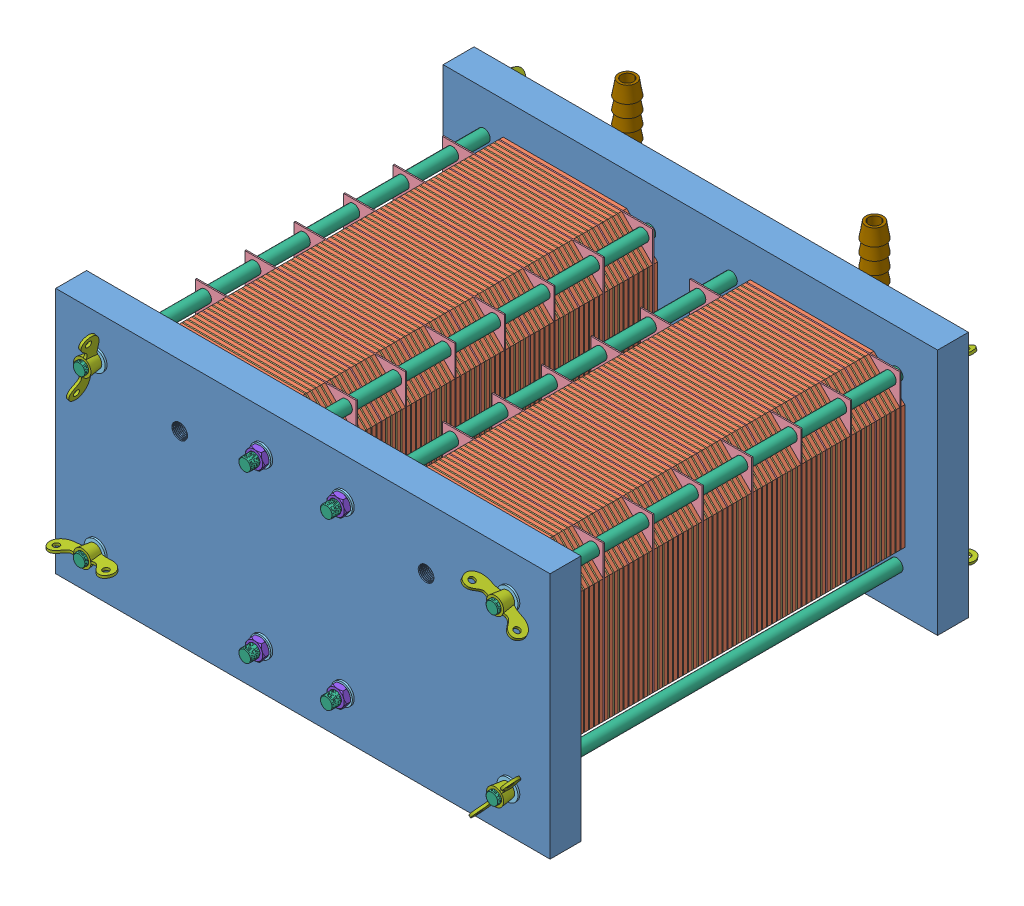
SolidWorks assembly Assem_Mine, configuration Default. Lengths in mm.
Overall size (400 216 390.22).
346 component instances, 9 part files, 95 mates.
Components (placement in the parent):
- Glass-1: Glass [Default] at (153.2199 -57.0551 297.1136) size (400 200 26.12)
- All Battery Block-1: All Battery Block [Default] at (-10.6585 129.0849 -81.5684) size (150 150 287)
  - Block Battery-1: Block Battery [Default] at (-175.922 -206.6429 -286.6039) size (150 150 40)
    - Gasket-12: Gasket [Default] at (244.3004 275.7985 390.286) size (150 150 3)
    - Plate-1-7: Plate-1 [Default] at (239.8004 279.4658 389.286) size (150 150 1)
    - Gasket-13: Gasket [Default] at (244.3004 275.7985 386.286) size (150 150 3)
    - Plate-1-8: Plate-1 [Default] at (239.8004 279.4658 385.286) size (150 150 1)
    - Gasket-14: Gasket [Default] at (244.3004 275.7985 382.286) size (150 150 3)
    - Plate-2-4: Plate-2 [Default] at (239.8004 279.4658 381.286) size (150 150 1)
    - Plate-1-10: Plate-1 [Default] at (239.8004 279.4658 393.286) size (150 150 1)
    - Gasket-16: Gasket [Default] at (244.3004 275.7985 394.286) size (150 150 3)
    - Plate-1-11: Plate-1 [Default] at (239.8004 279.4658 397.286) size (150 150 1)
    - Gasket-17: Gasket [Default] at (244.3004 275.7985 398.286) size (150 150 3)
    - Plate-2-5: Plate-2 [Default] at (239.8004 279.4658 402.286) x (-1 0 0) z (0 0 -1) size (150 150 1)
    - Gasket-18: Gasket [Default] at (244.3004 275.7985 402.286) size (150 150 3)
    - Plate-1-12: Plate-1 [Default] at (239.8004 279.4658 405.286) size (150 150 1)
    - Gasket-19: Gasket [Default] at (244.3004 275.7985 406.286) size (150 150 3)
    - Plate-1-13: Plate-1 [Default] at (239.8004 279.4658 409.286) size (150 150 1)
    - Gasket-20: Gasket [Default] at (244.3004 275.7985 410.286) size (150 150 3)
    - Plate-1-14: Plate-1 [Default] at (239.8004 279.4658 413.286) size (150 150 1)
    - Gasket-21: Gasket [Default] at (244.3004 275.7985 414.286) size (150 150 3)
    - Plate-1-15: Plate-1 [Default] at (239.8004 279.4658 417.286) size (150 150 1)
    - Gasket-22: Gasket [Default] at (244.3004 275.7985 418.286) size (150 150 3)
  - Block Battery-2: Block Battery [Default] at (-175.922 -206.6429 -246.6039) size (150 150 40)
    - Gasket-12: Gasket [Default] at (244.3004 275.7985 390.286) size (150 150 3)
    - Plate-1-7: Plate-1 [Default] at (239.8004 279.4658 389.286) size (150 150 1)
    - Gasket-13: Gasket [Default] at (244.3004 275.7985 386.286) size (150 150 3)
    - Plate-1-8: Plate-1 [Default] at (239.8004 279.4658 385.286) size (150 150 1)
    - Gasket-14: Gasket [Default] at (244.3004 275.7985 382.286) size (150 150 3)
    - Plate-2-4: Plate-2 [Default] at (239.8004 279.4658 381.286) size (150 150 1)
    - Plate-1-10: Plate-1 [Default] at (239.8004 279.4658 393.286) size (150 150 1)
    - Gasket-16: Gasket [Default] at (244.3004 275.7985 394.286) size (150 150 3)
    - Plate-1-11: Plate-1 [Default] at (239.8004 279.4658 397.286) size (150 150 1)
    - Gasket-17: Gasket [Default] at (244.3004 275.7985 398.286) size (150 150 3)
    - Plate-2-5: Plate-2 [Default] at (239.8004 279.4658 402.286) x (-1 0 0) z (0 0 -1) size (150 150 1)
    - Gasket-18: Gasket [Default] at (244.3004 275.7985 402.286) size (150 150 3)
    - Plate-1-12: Plate-1 [Default] at (239.8004 279.4658 405.286) size (150 150 1)
    - Gasket-19: Gasket [Default] at (244.3004 275.7985 406.286) size (150 150 3)
    - Plate-1-13: Plate-1 [Default] at (239.8004 279.4658 409.286) size (150 150 1)
    - Gasket-20: Gasket [Default] at (244.3004 275.7985 410.286) size (150 150 3)
    - Plate-1-14: Plate-1 [Default] at (239.8004 279.4658 413.286) size (150 150 1)
    - Gasket-21: Gasket [Default] at (244.3004 275.7985 414.286) size (150 150 3)
    - Plate-1-15: Plate-1 [Default] at (239.8004 279.4658 417.286) size (150 150 1)
    - Gasket-22: Gasket [Default] at (244.3004 275.7985 418.286) size (150 150 3)
  - Block Battery-3: Block Battery [Default] at (-175.922 -206.6429 -206.6039) size (150 150 40)
    - Gasket-12: Gasket [Default] at (244.3004 275.7985 390.286) size (150 150 3)
    - Plate-1-7: Plate-1 [Default] at (239.8004 279.4658 389.286) size (150 150 1)
    - Gasket-13: Gasket [Default] at (244.3004 275.7985 386.286) size (150 150 3)
    - Plate-1-8: Plate-1 [Default] at (239.8004 279.4658 385.286) size (150 150 1)
    - Gasket-14: Gasket [Default] at (244.3004 275.7985 382.286) size (150 150 3)
    - Plate-2-4: Plate-2 [Default] at (239.8004 279.4658 381.286) size (150 150 1)
    - Plate-1-10: Plate-1 [Default] at (239.8004 279.4658 393.286) size (150 150 1)
    - Gasket-16: Gasket [Default] at (244.3004 275.7985 394.286) size (150 150 3)
    - Plate-1-11: Plate-1 [Default] at (239.8004 279.4658 397.286) size (150 150 1)
    - Gasket-17: Gasket [Default] at (244.3004 275.7985 398.286) size (150 150 3)
    - Plate-2-5: Plate-2 [Default] at (239.8004 279.4658 402.286) x (-1 0 0) z (0 0 -1) size (150 150 1)
    - Gasket-18: Gasket [Default] at (244.3004 275.7985 402.286) size (150 150 3)
    - Plate-1-12: Plate-1 [Default] at (239.8004 279.4658 405.286) size (150 150 1)
    - Gasket-19: Gasket [Default] at (244.3004 275.7985 406.286) size (150 150 3)
    - Plate-1-13: Plate-1 [Default] at (239.8004 279.4658 409.286) size (150 150 1)
    - Gasket-20: Gasket [Default] at (244.3004 275.7985 410.286) size (150 150 3)
    - Plate-1-14: Plate-1 [Default] at (239.8004 279.4658 413.286) size (150 150 1)
    - Gasket-21: Gasket [Default] at (244.3004 275.7985 414.286) size (150 150 3)
    - Plate-1-15: Plate-1 [Default] at (239.8004 279.4658 417.286) size (150 150 1)
    - Gasket-22: Gasket [Default] at (244.3004 275.7985 418.286) size (150 150 3)
  - Block Battery-4: Block Battery [Default] at (-175.922 -206.6429 -166.6039) size (150 150 40)
    - Gasket-12: Gasket [Default] at (244.3004 275.7985 390.286) size (150 150 3)
    - Plate-1-7: Plate-1 [Default] at (239.8004 279.4658 389.286) size (150 150 1)
    - Gasket-13: Gasket [Default] at (244.3004 275.7985 386.286) size (150 150 3)
    - Plate-1-8: Plate-1 [Default] at (239.8004 279.4658 385.286) size (150 150 1)
    - Gasket-14: Gasket [Default] at (244.3004 275.7985 382.286) size (150 150 3)
    - Plate-2-4: Plate-2 [Default] at (239.8004 279.4658 381.286) size (150 150 1)
    - Plate-1-10: Plate-1 [Default] at (239.8004 279.4658 393.286) size (150 150 1)
    - Gasket-16: Gasket [Default] at (244.3004 275.7985 394.286) size (150 150 3)
    - Plate-1-11: Plate-1 [Default] at (239.8004 279.4658 397.286) size (150 150 1)
    - Gasket-17: Gasket [Default] at (244.3004 275.7985 398.286) size (150 150 3)
    - Plate-2-5: Plate-2 [Default] at (239.8004 279.4658 402.286) x (-1 0 0) z (0 0 -1) size (150 150 1)
    - Gasket-18: Gasket [Default] at (244.3004 275.7985 402.286) size (150 150 3)
    - Plate-1-12: Plate-1 [Default] at (239.8004 279.4658 405.286) size (150 150 1)
    - Gasket-19: Gasket [Default] at (244.3004 275.7985 406.286) size (150 150 3)
    - Plate-1-13: Plate-1 [Default] at (239.8004 279.4658 409.286) size (150 150 1)
    - Gasket-20: Gasket [Default] at (244.3004 275.7985 410.286) size (150 150 3)
    - Plate-1-14: Plate-1 [Default] at (239.8004 279.4658 413.286) size (150 150 1)
    - Gasket-21: Gasket [Default] at (244.3004 275.7985 414.286) size (150 150 3)
    - Plate-1-15: Plate-1 [Default] at (239.8004 279.4658 417.286) size (150 150 1)
    - Gasket-22: Gasket [Default] at (244.3004 275.7985 418.286) size (150 150 3)
  - Block Battery-5: Block Battery [Default] at (-175.922 -206.6429 -126.6039) size (150 150 40)
    - Gasket-12: Gasket [Default] at (244.3004 275.7985 390.286) size (150 150 3)
    - Plate-1-7: Plate-1 [Default] at (239.8004 279.4658 389.286) size (150 150 1)
    - Gasket-13: Gasket [Default] at (244.3004 275.7985 386.286) size (150 150 3)
    - Plate-1-8: Plate-1 [Default] at (239.8004 279.4658 385.286) size (150 150 1)
    - Gasket-14: Gasket [Default] at (244.3004 275.7985 382.286) size (150 150 3)
    - Plate-2-4: Plate-2 [Default] at (239.8004 279.4658 381.286) size (150 150 1)
    - Plate-1-10: Plate-1 [Default] at (239.8004 279.4658 393.286) size (150 150 1)
    - Gasket-16: Gasket [Default] at (244.3004 275.7985 394.286) size (150 150 3)
    - Plate-1-11: Plate-1 [Default] at (239.8004 279.4658 397.286) size (150 150 1)
    - Gasket-17: Gasket [Default] at (244.3004 275.7985 398.286) size (150 150 3)
    - Plate-2-5: Plate-2 [Default] at (239.8004 279.4658 402.286) x (-1 0 0) z (0 0 -1) size (150 150 1)
    - Gasket-18: Gasket [Default] at (244.3004 275.7985 402.286) size (150 150 3)
    - Plate-1-12: Plate-1 [Default] at (239.8004 279.4658 405.286) size (150 150 1)
    - Gasket-19: Gasket [Default] at (244.3004 275.7985 406.286) size (150 150 3)
    - Plate-1-13: Plate-1 [Default] at (239.8004 279.4658 409.286) size (150 150 1)
    - Gasket-20: Gasket [Default] at (244.3004 275.7985 410.286) size (150 150 3)
    - Plate-1-14: Plate-1 [Default] at (239.8004 279.4658 413.286) size (150 150 1)
    - Gasket-21: Gasket [Default] at (244.3004 275.7985 414.286) size (150 150 3)
    - Plate-1-15: Plate-1 [Default] at (239.8004 279.4658 417.286) size (150 150 1)
    - Gasket-22: Gasket [Default] at (244.3004 275.7985 418.286) size (150 150 3)
  - Block Battery-6: Block Battery [Default] at (-175.922 -206.6429 -86.6039) size (150 150 40)
    - Gasket-12: Gasket [Default] at (244.3004 275.7985 390.286) size (150 150 3)
    - Plate-1-7: Plate-1 [Default] at (239.8004 279.4658 389.286) size (150 150 1)
    - Gasket-13: Gasket [Default] at (244.3004 275.7985 386.286) size (150 150 3)
    - Plate-1-8: Plate-1 [Default] at (239.8004 279.4658 385.286) size (150 150 1)
    - Gasket-14: Gasket [Default] at (244.3004 275.7985 382.286) size (150 150 3)
    - Plate-2-4: Plate-2 [Default] at (239.8004 279.4658 381.286) size (150 150 1)
    - Plate-1-10: Plate-1 [Default] at (239.8004 279.4658 393.286) size (150 150 1)
    - Gasket-16: Gasket [Default] at (244.3004 275.7985 394.286) size (150 150 3)
    - Plate-1-11: Plate-1 [Default] at (239.8004 279.4658 397.286) size (150 150 1)
    - Gasket-17: Gasket [Default] at (244.3004 275.7985 398.286) size (150 150 3)
    - Plate-2-5: Plate-2 [Default] at (239.8004 279.4658 402.286) x (-1 0 0) z (0 0 -1) size (150 150 1)
    - Gasket-18: Gasket [Default] at (244.3004 275.7985 402.286) size (150 150 3)
    - Plate-1-12: Plate-1 [Default] at (239.8004 279.4658 405.286) size (150 150 1)
    - Gasket-19: Gasket [Default] at (244.3004 275.7985 406.286) size (150 150 3)
    - Plate-1-13: Plate-1 [Default] at (239.8004 279.4658 409.286) size (150 150 1)
    - Gasket-20: Gasket [Default] at (244.3004 275.7985 410.286) size (150 150 3)
    - Plate-1-14: Plate-1 [Default] at (239.8004 279.4658 413.286) size (150 150 1)
    - Gasket-21: Gasket [Default] at (244.3004 275.7985 414.286) size (150 150 3)
    - Plate-1-15: Plate-1 [Default] at (239.8004 279.4658 417.286) size (150 150 1)
    - Gasket-22: Gasket [Default] at (244.3004 275.7985 418.286) size (150 150 3)
  - Block Battery-7: Block Battery [Default] at (-175.922 -206.6429 -46.6039) size (150 150 40)
    - Gasket-12: Gasket [Default] at (244.3004 275.7985 390.286) size (150 150 3)
    - Plate-1-7: Plate-1 [Default] at (239.8004 279.4658 389.286) size (150 150 1)
    - Gasket-13: Gasket [Default] at (244.3004 275.7985 386.286) size (150 150 3)
    - Plate-1-8: Plate-1 [Default] at (239.8004 279.4658 385.286) size (150 150 1)
    - Gasket-14: Gasket [Default] at (244.3004 275.7985 382.286) size (150 150 3)
    - Plate-2-4: Plate-2 [Default] at (239.8004 279.4658 381.286) size (150 150 1)
    - Plate-1-10: Plate-1 [Default] at (239.8004 279.4658 393.286) size (150 150 1)
    - Gasket-16: Gasket [Default] at (244.3004 275.7985 394.286) size (150 150 3)
    - Plate-1-11: Plate-1 [Default] at (239.8004 279.4658 397.286) size (150 150 1)
    - Gasket-17: Gasket [Default] at (244.3004 275.7985 398.286) size (150 150 3)
    - Plate-2-5: Plate-2 [Default] at (239.8004 279.4658 402.286) x (-1 0 0) z (0 0 -1) size (150 150 1)
    - Gasket-18: Gasket [Default] at (244.3004 275.7985 402.286) size (150 150 3)
    - Plate-1-12: Plate-1 [Default] at (239.8004 279.4658 405.286) size (150 150 1)
    - Gasket-19: Gasket [Default] at (244.3004 275.7985 406.286) size (150 150 3)
    - Plate-1-13: Plate-1 [Default] at (239.8004 279.4658 409.286) size (150 150 1)
    - Gasket-20: Gasket [Default] at (244.3004 275.7985 410.286) size (150 150 3)
    - Plate-1-14: Plate-1 [Default] at (239.8004 279.4658 413.286) size (150 150 1)
    - Gasket-21: Gasket [Default] at (244.3004 275.7985 414.286) size (150 150 3)
    - Plate-1-15: Plate-1 [Default] at (239.8004 279.4658 417.286) size (150 150 1)
    - Gasket-22: Gasket [Default] at (244.3004 275.7985 418.286) size (150 150 3)
  - Plate-2-1: Plate-2 [Default] at (63.8784 72.8229 374.682) size (150 150 1)
  - Gasket-1: Gasket [Default] at (68.3784 69.1556 375.682) size (150 150 3)
  - Gasket-2: Gasket [Default] at (68.3784 69.1556 91.682) size (150 150 3)
- All Battery Block-2: All Battery Block [Default] at (189.3415 129.0849 -81.5684) size (150 150 287)
  - Block Battery-1: Block Battery [Default] at (-175.922 -206.6429 -286.6039) size (150 150 40)
    - Gasket-12: Gasket [Default] at (244.3004 275.7985 390.286) size (150 150 3)
    - Plate-1-7: Plate-1 [Default] at (239.8004 279.4658 389.286) size (150 150 1)
    - Gasket-13: Gasket [Default] at (244.3004 275.7985 386.286) size (150 150 3)
    - Plate-1-8: Plate-1 [Default] at (239.8004 279.4658 385.286) size (150 150 1)
    - Gasket-14: Gasket [Default] at (244.3004 275.7985 382.286) size (150 150 3)
    - Plate-2-4: Plate-2 [Default] at (239.8004 279.4658 381.286) size (150 150 1)
    - Plate-1-10: Plate-1 [Default] at (239.8004 279.4658 393.286) size (150 150 1)
    - Gasket-16: Gasket [Default] at (244.3004 275.7985 394.286) size (150 150 3)
    - Plate-1-11: Plate-1 [Default] at (239.8004 279.4658 397.286) size (150 150 1)
    - Gasket-17: Gasket [Default] at (244.3004 275.7985 398.286) size (150 150 3)
    - Plate-2-5: Plate-2 [Default] at (239.8004 279.4658 402.286) x (-1 0 0) z (0 0 -1) size (150 150 1)
    - Gasket-18: Gasket [Default] at (244.3004 275.7985 402.286) size (150 150 3)
    - Plate-1-12: Plate-1 [Default] at (239.8004 279.4658 405.286) size (150 150 1)
    - Gasket-19: Gasket [Default] at (244.3004 275.7985 406.286) size (150 150 3)
    - Plate-1-13: Plate-1 [Default] at (239.8004 279.4658 409.286) size (150 150 1)
    - Gasket-20: Gasket [Default] at (244.3004 275.7985 410.286) size (150 150 3)
    - Plate-1-14: Plate-1 [Default] at (239.8004 279.4658 413.286) size (150 150 1)
    - Gasket-21: Gasket [Default] at (244.3004 275.7985 414.286) size (150 150 3)
    - Plate-1-15: Plate-1 [Default] at (239.8004 279.4658 417.286) size (150 150 1)
    - Gasket-22: Gasket [Default] at (244.3004 275.7985 418.286) size (150 150 3)
  - Block Battery-2: Block Battery [Default] at (-175.922 -206.6429 -246.6039) size (150 150 40)
    - Gasket-12: Gasket [Default] at (244.3004 275.7985 390.286) size (150 150 3)
    - Plate-1-7: Plate-1 [Default] at (239.8004 279.4658 389.286) size (150 150 1)
    - Gasket-13: Gasket [Default] at (244.3004 275.7985 386.286) size (150 150 3)
    - Plate-1-8: Plate-1 [Default] at (239.8004 279.4658 385.286) size (150 150 1)
    - Gasket-14: Gasket [Default] at (244.3004 275.7985 382.286) size (150 150 3)
    - Plate-2-4: Plate-2 [Default] at (239.8004 279.4658 381.286) size (150 150 1)
    - Plate-1-10: Plate-1 [Default] at (239.8004 279.4658 393.286) size (150 150 1)
    - Gasket-16: Gasket [Default] at (244.3004 275.7985 394.286) size (150 150 3)
    - Plate-1-11: Plate-1 [Default] at (239.8004 279.4658 397.286) size (150 150 1)
    - Gasket-17: Gasket [Default] at (244.3004 275.7985 398.286) size (150 150 3)
    - Plate-2-5: Plate-2 [Default] at (239.8004 279.4658 402.286) x (-1 0 0) z (0 0 -1) size (150 150 1)
    - Gasket-18: Gasket [Default] at (244.3004 275.7985 402.286) size (150 150 3)
    - Plate-1-12: Plate-1 [Default] at (239.8004 279.4658 405.286) size (150 150 1)
    - Gasket-19: Gasket [Default] at (244.3004 275.7985 406.286) size (150 150 3)
    - Plate-1-13: Plate-1 [Default] at (239.8004 279.4658 409.286) size (150 150 1)
    - Gasket-20: Gasket [Default] at (244.3004 275.7985 410.286) size (150 150 3)
    - Plate-1-14: Plate-1 [Default] at (239.8004 279.4658 413.286) size (150 150 1)
    - Gasket-21: Gasket [Default] at (244.3004 275.7985 414.286) size (150 150 3)
    - Plate-1-15: Plate-1 [Default] at (239.8004 279.4658 417.286) size (150 150 1)
    - Gasket-22: Gasket [Default] at (244.3004 275.7985 418.286) size (150 150 3)
  - Block Battery-3: Block Battery [Default] at (-175.922 -206.6429 -206.6039) size (150 150 40)
    - Gasket-12: Gasket [Default] at (244.3004 275.7985 390.286) size (150 150 3)
    - Plate-1-7: Plate-1 [Default] at (239.8004 279.4658 389.286) size (150 150 1)
    - Gasket-13: Gasket [Default] at (244.3004 275.7985 386.286) size (150 150 3)
    - Plate-1-8: Plate-1 [Default] at (239.8004 279.4658 385.286) size (150 150 1)
    - Gasket-14: Gasket [Default] at (244.3004 275.7985 382.286) size (150 150 3)
    - Plate-2-4: Plate-2 [Default] at (239.8004 279.4658 381.286) size (150 150 1)
    - Plate-1-10: Plate-1 [Default] at (239.8004 279.4658 393.286) size (150 150 1)
    - Gasket-16: Gasket [Default] at (244.3004 275.7985 394.286) size (150 150 3)
    - Plate-1-11: Plate-1 [Default] at (239.8004 279.4658 397.286) size (150 150 1)
    - Gasket-17: Gasket [Default] at (244.3004 275.7985 398.286) size (150 150 3)
    - Plate-2-5: Plate-2 [Default] at (239.8004 279.4658 402.286) x (-1 0 0) z (0 0 -1) size (150 150 1)
    - Gasket-18: Gasket [Default] at (244.3004 275.7985 402.286) size (150 150 3)
    - Plate-1-12: Plate-1 [Default] at (239.8004 279.4658 405.286) size (150 150 1)
    - Gasket-19: Gasket [Default] at (244.3004 275.7985 406.286) size (150 150 3)
    - Plate-1-13: Plate-1 [Default] at (239.8004 279.4658 409.286) size (150 150 1)
    - Gasket-20: Gasket [Default] at (244.3004 275.7985 410.286) size (150 150 3)
    - Plate-1-14: Plate-1 [Default] at (239.8004 279.4658 413.286) size (150 150 1)
    - Gasket-21: Gasket [Default] at (244.3004 275.7985 414.286) size (150 150 3)
    - Plate-1-15: Plate-1 [Default] at (239.8004 279.4658 417.286) size (150 150 1)
    - Gasket-22: Gasket [Default] at (244.3004 275.7985 418.286) size (150 150 3)
  - Block Battery-4: Block Battery [Default] at (-175.922 -206.6429 -166.6039) size (150 150 40)
    - Gasket-12: Gasket [Default] at (244.3004 275.7985 390.286) size (150 150 3)
    - Plate-1-7: Plate-1 [Default] at (239.8004 279.4658 389.286) size (150 150 1)
    - Gasket-13: Gasket [Default] at (244.3004 275.7985 386.286) size (150 150 3)
    - Plate-1-8: Plate-1 [Default] at (239.8004 279.4658 385.286) size (150 150 1)
    - Gasket-14: Gasket [Default] at (244.3004 275.7985 382.286) size (150 150 3)
    - Plate-2-4: Plate-2 [Default] at (239.8004 279.4658 381.286) size (150 150 1)
    - Plate-1-10: Plate-1 [Default] at (239.8004 279.4658 393.286) size (150 150 1)
    - Gasket-16: Gasket [Default] at (244.3004 275.7985 394.286) size (150 150 3)
    - Plate-1-11: Plate-1 [Default] at (239.8004 279.4658 397.286) size (150 150 1)
    - Gasket-17: Gasket [Default] at (244.3004 275.7985 398.286) size (150 150 3)
    - Plate-2-5: Plate-2 [Default] at (239.8004 279.4658 402.286) x (-1 0 0) z (0 0 -1) size (150 150 1)
    - Gasket-18: Gasket [Default] at (244.3004 275.7985 402.286) size (150 150 3)
    - Plate-1-12: Plate-1 [Default] at (239.8004 279.4658 405.286) size (150 150 1)
    - Gasket-19: Gasket [Default] at (244.3004 275.7985 406.286) size (150 150 3)
    - Plate-1-13: Plate-1 [Default] at (239.8004 279.4658 409.286) size (150 150 1)
    - Gasket-20: Gasket [Default] at (244.3004 275.7985 410.286) size (150 150 3)
    - Plate-1-14: Plate-1 [Default] at (239.8004 279.4658 413.286) size (150 150 1)
    - Gasket-21: Gasket [Default] at (244.3004 275.7985 414.286) size (150 150 3)
    - Plate-1-15: Plate-1 [Default] at (239.8004 279.4658 417.286) size (150 150 1)
    - Gasket-22: Gasket [Default] at (244.3004 275.7985 418.286) size (150 150 3)
  - Block Battery-5: Block Battery [Default] at (-175.922 -206.6429 -126.6039) size (150 150 40)
    - Gasket-12: Gasket [Default] at (244.3004 275.7985 390.286) size (150 150 3)
    - Plate-1-7: Plate-1 [Default] at (239.8004 279.4658 389.286) size (150 150 1)
    - Gasket-13: Gasket [Default] at (244.3004 275.7985 386.286) size (150 150 3)
    - Plate-1-8: Plate-1 [Default] at (239.8004 279.4658 385.286) size (150 150 1)
    - Gasket-14: Gasket [Default] at (244.3004 275.7985 382.286) size (150 150 3)
    - Plate-2-4: Plate-2 [Default] at (239.8004 279.4658 381.286) size (150 150 1)
    - Plate-1-10: Plate-1 [Default] at (239.8004 279.4658 393.286) size (150 150 1)
    - Gasket-16: Gasket [Default] at (244.3004 275.7985 394.286) size (150 150 3)
    - Plate-1-11: Plate-1 [Default] at (239.8004 279.4658 397.286) size (150 150 1)
    - Gasket-17: Gasket [Default] at (244.3004 275.7985 398.286) size (150 150 3)
    - Plate-2-5: Plate-2 [Default] at (239.8004 279.4658 402.286) x (-1 0 0) z (0 0 -1) size (150 150 1)
    - Gasket-18: Gasket [Default] at (244.3004 275.7985 402.286) size (150 150 3)
    - Plate-1-12: Plate-1 [Default] at (239.8004 279.4658 405.286) size (150 150 1)
    - Gasket-19: Gasket [Default] at (244.3004 275.7985 406.286) size (150 150 3)
    - Plate-1-13: Plate-1 [Default] at (239.8004 279.4658 409.286) size (150 150 1)
    - Gasket-20: Gasket [Default] at (244.3004 275.7985 410.286) size (150 150 3)
    - Plate-1-14: Plate-1 [Default] at (239.8004 279.4658 413.286) size (150 150 1)
    - Gasket-21: Gasket [Default] at (244.3004 275.7985 414.286) size (150 150 3)
    - Plate-1-15: Plate-1 [Default] at (239.8004 279.4658 417.286) size (150 150 1)
    - Gasket-22: Gasket [Default] at (244.3004 275.7985 418.286) size (150 150 3)
  - Block Battery-6: Block Battery [Default] at (-175.922 -206.6429 -86.6039) size (150 150 40)
    - Gasket-12: Gasket [Default] at (244.3004 275.7985 390.286) size (150 150 3)
    - Plate-1-7: Plate-1 [Default] at (239.8004 279.4658 389.286) size (150 150 1)
    - Gasket-13: Gasket [Default] at (244.3004 275.7985 386.286) size (150 150 3)
    - Plate-1-8: Plate-1 [Default] at (239.8004 279.4658 385.286) size (150 150 1)
    - Gasket-14: Gasket [Default] at (244.3004 275.7985 382.286) size (150 150 3)
    - Plate-2-4: Plate-2 [Default] at (239.8004 279.4658 381.286) size (150 150 1)
    - Plate-1-10: Plate-1 [Default] at (239.8004 279.4658 393.286) size (150 150 1)
    - Gasket-16: Gasket [Default] at (244.3004 275.7985 394.286) size (150 150 3)
    - Plate-1-11: Plate-1 [Default] at (239.8004 279.4658 397.286) size (150 150 1)
    - Gasket-17: Gasket [Default] at (244.3004 275.7985 398.286) size (150 150 3)
    - Plate-2-5: Plate-2 [Default] at (239.8004 279.4658 402.286) x (-1 0 0) z (0 0 -1) size (150 150 1)
    - Gasket-18: Gasket [Default] at (244.3004 275.7985 402.286) size (150 150 3)
    - Plate-1-12: Plate-1 [Default] at (239.8004 279.4658 405.286) size (150 150 1)
    - Gasket-19: Gasket [Default] at (244.3004 275.7985 406.286) size (150 150 3)
    - Plate-1-13: Plate-1 [Default] at (239.8004 279.4658 409.286) size (150 150 1)
    - Gasket-20: Gasket [Default] at (244.3004 275.7985 410.286) size (150 150 3)
    - Plate-1-14: Plate-1 [Default] at (239.8004 279.4658 413.286) size (150 150 1)
    - Gasket-21: Gasket [Default] at (244.3004 275.7985 414.286) size (150 150 3)
    - Plate-1-15: Plate-1 [Default] at (239.8004 279.4658 417.286) size (150 150 1)
    - Gasket-22: Gasket [Default] at (244.3004 275.7985 418.286) size (150 150 3)
  - Block Battery-7: Block Battery [Default] at (-175.922 -206.6429 -46.6039) size (150 150 40)
    - Gasket-12: Gasket [Default] at (244.3004 275.7985 390.286) size (150 150 3)
    - Plate-1-7: Plate-1 [Default] at (239.8004 279.4658 389.286) size (150 150 1)
    - Gasket-13: Gasket [Default] at (244.3004 275.7985 386.286) size (150 150 3)
    - Plate-1-8: Plate-1 [Default] at (239.8004 279.4658 385.286) size (150 150 1)
    - Gasket-14: Gasket [Default] at (244.3004 275.7985 382.286) size (150 150 3)
    - Plate-2-4: Plate-2 [Default] at (239.8004 279.4658 381.286) size (150 150 1)
    - Plate-1-10: Plate-1 [Default] at (239.8004 279.4658 393.286) size (150 150 1)
    - Gasket-16: Gasket [Default] at (244.3004 275.7985 394.286) size (150 150 3)
    - Plate-1-11: Plate-1 [Default] at (239.8004 279.4658 397.286) size (150 150 1)
    - Gasket-17: Gasket [Default] at (244.3004 275.7985 398.286) size (150 150 3)
    - Plate-2-5: Plate-2 [Default] at (239.8004 279.4658 402.286) x (-1 0 0) z (0 0 -1) size (150 150 1)
    - Gasket-18: Gasket [Default] at (244.3004 275.7985 402.286) size (150 150 3)
    - Plate-1-12: Plate-1 [Default] at (239.8004 279.4658 405.286) size (150 150 1)
    - Gasket-19: Gasket [Default] at (244.3004 275.7985 406.286) size (150 150 3)
    - Plate-1-13: Plate-1 [Default] at (239.8004 279.4658 409.286) size (150 150 1)
    - Gasket-20: Gasket [Default] at (244.3004 275.7985 410.286) size (150 150 3)
    - Plate-1-14: Plate-1 [Default] at (239.8004 279.4658 413.286) size (150 150 1)
    - Gasket-21: Gasket [Default] at (244.3004 275.7985 414.286) size (150 150 3)
    - Plate-1-15: Plate-1 [Default] at (239.8004 279.4658 417.286) size (150 150 1)
    - Gasket-22: Gasket [Default] at (244.3004 275.7985 418.286) size (150 150 3)
  - Plate-2-1: Plate-2 [Default] at (63.8784 72.8229 374.682) size (150 150 1)
  - Gasket-1: Gasket [Default] at (68.3784 69.1556 375.682) size (150 150 3)
  - Gasket-2: Gasket [Default] at (68.3784 69.1556 91.682) size (150 150 3)
- Glass-2: Glass [Default] at (153.2199 -57.0551 -16.3864) size (400 200 26.12)
- Washer-1: Washer [Default] at (320.2199 268.9078 -17.8864) size (17 17 1.5)
- Screw-2: Screw [Default] at (-13.7801 268.9078 -30.3864) size (10.01 10.25 367.6)
- Washer-2: Washer [Default] at (-13.7801 268.9078 322.1136) size (17 17 1.5)
- Vint-3: Vint [Default] at (320.2199 268.9078 -27.8864) x (0.941946 0.335764 0) z (0 0 1) size (52.29 14 17.39)
- Vint-4: Vint [Default] at (320.2199 134.9078 -27.8864) x (-0.98956 0.144119 0) z (0 0 1) size (52.29 14 17.39)
- Washer-3: Washer [Default] at (-13.7801 268.9078 -17.8864) size (17 17 1.5)
- Screw-4: Screw [Default] at (-13.7801 134.9078 -30.3864) size (10.01 10.25 367.6)
- Screw-5: Screw [Default] at (120.2199 268.9078 -30.3864) size (10.01 10.25 367.6)
- Washer-4: Washer [Default] at (120.2199 268.9078 322.1136) size (17 17 1.5)
- Washer-5: Washer [Default] at (-13.7801 134.9078 322.1136) size (17 17 1.5)
- Washer-6: Washer [Default] at (120.2199 268.9078 -17.8864) size (17 17 1.5)
- Washer-7: Washer [Default] at (-13.7801 134.9078 -17.8864) size (17 17 1.5)
- Screw-6: Screw [Default] at (186.2199 268.9078 -30.3864) size (10.01 10.25 367.6)
- Washer-8: Washer [Default] at (186.2199 268.9078 -17.8864) size (17 17 1.5)
- Screw-7: Screw [Default] at (320.2199 268.9078 -30.3864) size (10.01 10.25 367.6)
- Screw-8: Screw [Default] at (320.2199 134.9078 -30.3864) size (10.01 10.25 367.6)
- Screw-9: Screw [Default] at (186.2199 134.9078 -30.3864) size (10.01 10.25 367.6)
- Screw-10: Screw [Default] at (120.2199 134.9078 -30.3864) size (10.01 10.25 367.6)
- Washer-9: Washer [Default] at (320.2199 268.9078 322.1136) size (17 17 1.5)
- Washer-10: Washer [Default] at (320.2199 134.9078 322.1136) size (17 17 1.5)
- Washer-11: Washer [Default] at (186.2199 268.9078 322.1136) size (17 17 1.5)
- Washer-12: Washer [Default] at (186.2199 134.9078 322.1136) size (17 17 1.5)
- Washer-13: Washer [Default] at (120.2199 134.9078 322.1136) size (17 17 1.5)
- Washer-14: Washer [Default] at (320.2199 134.9078 -17.8864) size (17 17 1.5)
- Washer-15: Washer [Default] at (120.2199 134.9078 -17.8864) size (17 17 1.5)
- Washer-16: Washer [Default] at (186.2199 134.9078 -17.8864) size (17 17 1.5)
- Vint-5: Vint [Default] at (-13.7801 268.9078 -27.8864) x (0.551468 -0.834196 0) z (0 0 1) size (52.29 14 17.39)
- Vint-6: Vint [Default] at (-13.7801 134.9078 -27.8864) x (0.868451 -0.495776 0) z (0 0 1) size (52.29 14 17.39)
- Vint-7: Vint [Default] at (320.2199 268.9078 333.6136) x (0.906472 -0.422266 0) z (0 0 -1) size (52.29 14 17.39)
- Vint-8: Vint [Default] at (-13.7801 268.9078 333.6136) x (0.243567 0.969884 0) z (0 0 -1) size (52.29 14 17.39)
- Vint-9: Vint [Default] at (-13.7801 134.9078 333.6136) x (0.997696 0.067837 0) z (0 0 -1) size (52.29 14 17.39)
- Vint-10: Vint [Default] at (320.2199 134.9078 333.6136) x (0.627423 0.778678 0) z (0 0 -1) size (52.29 14 17.39)
- Mutter M10-1: Mutter M10 [Default] at (186.2199 268.9078 323.6136) size (16.8 16.24 6.22)
- Mutter M10-2: Mutter M10 [Default] at (120.2199 268.9078 -22.8864) size (16.8 16.24 6.22)
- Mutter M10-3: Mutter M10 [Default] at (120.2199 268.9078 323.6136) size (16.8 16.24 6.22)
- Mutter M10-4: Mutter M10 [Default] at (120.2199 134.9078 323.6136) size (16.8 16.24 6.22)
- Mutter M10-5: Mutter M10 [Default] at (186.2199 134.9078 323.6136) size (16.8 16.24 6.22)
- Mutter M10-6: Mutter M10 [Default] at (186.2199 134.9078 -22.8864) size (16.8 16.24 6.22)
- Mutter M10-7: Mutter M10 [Default] at (186.2199 268.9078 -22.8864) size (16.8 16.24 6.22)
- Mutter M10-8: Mutter M10 [Default] at (120.2199 134.9078 -22.8864) size (16.8 16.24 6.22)
- branch pipe-1: branch pipe [Default] at (53.2199 251.9078 -32.3864) x (-1 0 0) z (0 0 1) size (18.58 74 52.8)
- branch pipe-2: branch pipe [Default] at (253.2199 251.9078 -32.3864) x (-1 0 0) z (0 0 1) size (18.58 74 52.8)
Mates (geometry in assembly coordinates):
- Concentric1: concentric anti-aligned: circle of Glass-1; circle of All Battery Block-1/Plate-2-1
- Distance1: distance = 0 mm anti-aligned: plane of All Battery Block-1/Gasket-1 through (57.7199 198.2405 297.1136) normal (0 0 1); plane of Glass-1 through (153.2199 -57.0551 297.1136) normal (0 0 -1)
- Parallel1: parallel aligned: line of Glass-1 through (-46.7801 101.9078 297.1136) axis (1 0 0); line of All Battery Block-1/Gasket-1 through (3.2199 126.9078 294.1136) axis (1 0 0)
- Concentric2: concentric anti-aligned: circle of Glass-1; circle of All Battery Block-2/Plate-2-1
- Distance2: distance = 0 mm anti-aligned: plane of All Battery Block-2/Gasket-1 through (257.7199 198.2405 297.1136) normal (0 0 1); plane of Glass-1 through (153.2199 -57.0551 297.1136) normal (0 0 -1)
- Parallel2: parallel aligned: line of Glass-1 through (-46.7801 101.9078 297.1136) axis (1 0 0); line of All Battery Block-2/Gasket-1 through (203.2199 126.9078 297.1136) axis (1 0 0)
- Parallel3: parallel aligned: line of Glass-1 through (-46.7801 101.9078 297.1136) axis (1 0 0); line of All Battery Block-2/Gasket-1 through (203.2199 126.9078 297.1136) axis (1 0 0)
- Concentric3: concentric anti-aligned: circle of All Battery Block-2/Block Battery-1/Plate-2-4; circle of Glass-2
- Concentric4: concentric aligned: circle of Glass-1; circle of Glass-2
- Concentric6: concentric aligned: cylinder of Glass-1 through (-13.7801 268.9078 322.1136) axis (0 0 -1) radius 5; cylinder of Screw-2 through (-13.7801 268.9078 336.1136) axis (0 0 -1) radius 5
- Distance7: distance = 14 mm: plane of Screw-2 through (-13.7801 268.9078 336.1136) normal (0 0 1); line of Glass-1 through (353.2199 301.9078 322.1136) axis (-1 0 0)
- Concentric7: concentric anti-aligned: cylinder of Screw-2 through (-13.7801 268.9078 336.1136) axis (0 0 -1) radius 5; circle of Washer-2
- Distance10: distance = 25 mm aligned: plane of Washer-2 through (-13.7801 268.9078 322.1136) normal (0 0 -1); plane of Glass-1 through (153.2199 -57.0551 297.1136) normal (0 0 -1)
- Concentric9: concentric anti-aligned: cylinder of Screw-2 through (-13.7801 268.9078 336.1136) axis (0 0 -1) radius 5; circle of Washer-3
- Distance11: distance = 0 mm anti-aligned: plane of Washer-3 through (-13.7801 268.9078 -16.3864) normal (0 0 1); plane of Glass-2 through (153.2199 -57.0551 -16.3864) normal (0 0 -1)
- Concentric10: concentric aligned: cylinder of Glass-1 through (-13.7801 134.9078 322.1136) axis (0 0 -1) radius 5; cylinder of Screw-4 through (-13.7801 134.9078 336.1136) axis (0 0 -1) radius 5
- Distance12: distance = 14 mm: plane of Screw-4 through (-13.7801 134.9078 336.1136) normal (0 0 1); line of Glass-1 through (-46.7801 101.9078 322.1136) axis (1 0 0)
- Concentric11: concentric aligned: cylinder of Glass-1 through (120.2199 268.9078 322.1136) axis (0 0 -1) radius 5; cylinder of Screw-5 through (120.2199 268.9078 336.1136) axis (0 0 -1) radius 5
- Distance13: distance = 14 mm aligned: plane of Screw-5 through (120.2199 268.9078 -30.3864) normal (0 0 -1); plane of Glass-2 through (153.2199 -57.0551 -16.3864) normal (0 0 -1)
- Concentric12: concentric anti-aligned: cylinder of Screw-4 through (-13.7801 134.9078 336.1136) axis (0 0 -1) radius 5; circle of Washer-5
- Parallel5: parallel anti-aligned: plane of Glass-1 through (153.2199 -57.0551 297.1136) normal (0 0 -1); plane of Washer-5 through (-13.7801 134.9078 323.6136) normal (0 0 1)
- Distance15: distance = 25 mm aligned: plane of Washer-5 through (-13.7801 134.9078 322.1136) normal (0 0 -1); plane of Glass-1 through (153.2199 -57.0551 297.1136) normal (0 0 -1)
- Distance16: distance = 39 mm anti-aligned: plane of Screw-5 through (120.2199 268.9078 336.1136) normal (0 0 1); plane of Glass-1 through (153.2199 -57.0551 297.1136) normal (0 0 -1)
- Concentric13: concentric anti-aligned: cylinder of Screw-5 through (120.2199 268.9078 336.1136) axis (0 0 -1) radius 5; circle of Washer-4
- Distance17: distance = 25 mm aligned: plane of Washer-4 through (120.2199 268.9078 322.1136) normal (0 0 -1); plane of Glass-1 through (153.2199 -57.0551 297.1136) normal (0 0 -1)
- Concentric14: concentric anti-aligned: cylinder of Screw-4 through (-13.7801 134.9078 336.1136) axis (0 0 -1) radius 5; circle of Washer-7
- Distance18: distance = 0 mm anti-aligned: plane of Washer-7 through (-13.7801 134.9078 -16.3864) normal (0 0 1); plane of Glass-2 through (153.2199 -57.0551 -16.3864) normal (0 0 -1)
- Concentric15: concentric anti-aligned: cylinder of Screw-5 through (120.2199 268.9078 336.1136) axis (0 0 -1) radius 5; circle of Washer-6
- Distance19: distance = 0 mm anti-aligned: plane of Washer-6 through (120.2199 268.9078 -16.3864) normal (0 0 1); plane of Glass-2 through (153.2199 -57.0551 -16.3864) normal (0 0 -1)
- Concentric16: concentric aligned: cylinder of Glass-2 through (186.2199 268.9078 8.6136) axis (0 0 -1) radius 5; cylinder of Screw-6 through (186.2199 268.9078 336.1136) axis (0 0 -1) radius 5
- Distance20: distance = 14 mm aligned: plane of Screw-6 through (186.2199 268.9078 -30.3864) normal (0 0 -1); plane of Glass-2 through (153.2199 -57.0551 -16.3864) normal (0 0 -1)
- Concentric17: concentric anti-aligned: cylinder of Screw-6 through (186.2199 268.9078 336.1136) axis (0 0 -1) radius 5; circle of Washer-8
- Distance21: distance = 0 mm anti-aligned: plane of Washer-8 through (186.2199 268.9078 -16.3864) normal (0 0 1); plane of Glass-2 through (153.2199 -57.0551 -16.3864) normal (0 0 -1)
- Concentric18: concentric aligned: cylinder of Glass-2 through (320.2199 268.9078 8.6136) axis (0 0 -1) radius 5; cylinder of Screw-7 through (320.2199 268.9078 336.1136) axis (0 0 -1) radius 5
- Distance22: distance = 14 mm aligned: plane of Screw-7 through (320.2199 268.9078 -30.3864) normal (0 0 -1); plane of Glass-2 through (153.2199 -57.0551 -16.3864) normal (0 0 -1)
- Concentric19: concentric aligned: cylinder of Glass-2 through (120.2199 134.9078 8.6136) axis (0 0 -1) radius 5; cylinder of Screw-10 through (120.2199 134.9078 336.1136) axis (0 0 -1) radius 5
- Concentric20: concentric aligned: circle of Glass-2; cylinder of Screw-9 through (186.2199 134.9078 336.1136) axis (0 0 -1) radius 5
- Concentric21: concentric aligned: cylinder of Glass-2 through (320.2199 134.9078 8.6136) axis (0 0 -1) radius 5; cylinder of Screw-8 through (320.2199 134.9078 336.1136) axis (0 0 -1) radius 5
- Distance23: distance = 14 mm aligned: plane of Screw-10 through (120.2199 134.9078 -30.3864) normal (0 0 -1); plane of Glass-2 through (153.2199 -57.0551 -16.3864) normal (0 0 -1)
- Distance24: distance = 14 mm aligned: plane of Screw-9 through (186.2199 134.9078 -30.3864) normal (0 0 -1); plane of Glass-2 through (153.2199 -57.0551 -16.3864) normal (0 0 -1)
- Distance25: distance = 14 mm aligned: plane of Screw-8 through (320.2199 134.9078 -30.3864) normal (0 0 -1); plane of Glass-2 through (153.2199 -57.0551 -16.3864) normal (0 0 -1)
- Concentric22: concentric anti-aligned: cylinder of Screw-9 through (186.2199 134.9078 336.1136) axis (0 0 -1) radius 5; circle of Washer-12
- Distance26: distance = 25 mm aligned: plane of Washer-12 through (186.2199 134.9078 322.1136) normal (0 0 -1); plane of Glass-1 through (153.2199 -57.0551 297.1136) normal (0 0 -1)
- Concentric23: concentric anti-aligned: cylinder of Glass-1 through (120.2199 134.9078 322.1136) axis (0 0 -1) radius 5; circle of Washer-13
- Distance27: distance = 25 mm aligned: plane of Washer-13 through (120.2199 134.9078 322.1136) normal (0 0 -1); plane of Glass-1 through (153.2199 -57.0551 297.1136) normal (0 0 -1)
- Concentric24: concentric anti-aligned: cylinder of Screw-6 through (186.2199 268.9078 336.1136) axis (0 0 -1) radius 5; circle of Washer-11
- Distance28: distance = 25 mm aligned: plane of Washer-11 through (186.2199 268.9078 322.1136) normal (0 0 -1); plane of Glass-1 through (153.2199 -57.0551 297.1136) normal (0 0 -1)
- Concentric25: concentric anti-aligned: cylinder of Screw-7 through (320.2199 268.9078 336.1136) axis (0 0 -1) radius 5; circle of Washer-9
- Distance29: distance = 25 mm aligned: plane of Washer-9 through (320.2199 268.9078 322.1136) normal (0 0 -1); plane of Glass-1 through (153.2199 -57.0551 297.1136) normal (0 0 -1)
- Concentric26: concentric anti-aligned: cylinder of Glass-1 through (320.2199 134.9078 322.1136) axis (0 0 -1) radius 5; circle of Washer-10
- Distance30: distance = 25 mm aligned: plane of Washer-10 through (320.2199 134.9078 322.1136) normal (0 0 -1); plane of Glass-1 through (153.2199 -57.0551 297.1136) normal (0 0 -1)
- Concentric27: concentric anti-aligned: circle of Washer-1; cylinder of Screw-7 through (320.2199 268.9078 336.1136) axis (0 0 -1) radius 5
- Distance31: distance = 0 mm anti-aligned: plane of Washer-1 through (320.2199 268.9078 -16.3864) normal (0 0 1); plane of Glass-2 through (153.2199 -57.0551 -16.3864) normal (0 0 -1)
- Concentric28: concentric anti-aligned: cylinder of Screw-10 through (120.2199 134.9078 336.1136) axis (0 0 -1) radius 5; circle of Washer-15
- Concentric29: concentric anti-aligned: cylinder of Screw-9 through (186.2199 134.9078 336.1136) axis (0 0 -1) radius 5; circle of Washer-16
- Distance32: distance = 0 mm anti-aligned: plane of Washer-15 through (120.2199 134.9078 -16.3864) normal (0 0 1); plane of Glass-2 through (153.2199 -57.0551 -16.3864) normal (0 0 -1)
- Distance33: distance = 0 mm anti-aligned: plane of Washer-16 through (186.2199 134.9078 -16.3864) normal (0 0 1); plane of Glass-2 through (153.2199 -57.0551 -16.3864) normal (0 0 -1)
- Concentric30: concentric anti-aligned: cylinder of Screw-8 through (320.2199 134.9078 336.1136) axis (0 0 -1) radius 5; circle of Washer-14
- Distance34: distance = 0 mm anti-aligned: plane of Washer-14 through (320.2199 134.9078 -16.3864) normal (0 0 1); plane of Glass-2 through (153.2199 -57.0551 -16.3864) normal (0 0 -1)
- Concentric31: concentric anti-aligned: circle of Vint-3; cylinder of Screw-7 through (320.2199 268.9078 336.1136) axis (0 0 -1) radius 5
- Distance36: distance = 0 mm anti-aligned: plane of Vint-3 through (320.2199 268.9078 -17.8864) normal (0 0 1); plane of Washer-1 through (320.2199 268.9078 -17.8864) normal (0 0 -1)
- Concentric33: concentric aligned: circle of Vint-4; circle of Washer-14
- Distance37: distance = 0 mm anti-aligned: plane of Vint-4 through (320.2199 134.9078 -17.8864) normal (0 0 1); plane of Washer-14 through (320.2199 134.9078 -17.8864) normal (0 0 -1)
- Concentric34: concentric aligned: circle of Washer-3; circle of Vint-5
- Concentric35: concentric aligned: circle of Washer-7; circle of Vint-6
- Distance38: distance = 0 mm anti-aligned: plane of Vint-5 through (-13.7801 268.9078 -17.8864) normal (0 0 1); plane of Washer-3 through (-13.7801 268.9078 -17.8864) normal (0 0 -1)
- Distance39: distance = 0 mm anti-aligned: plane of Vint-6 through (-13.7801 134.9078 -17.8864) normal (0 0 1); plane of Washer-7 through (-13.7801 134.9078 -17.8864) normal (0 0 -1)
- Concentric36: concentric anti-aligned: circle of Washer-9; circle of Vint-7
- Concentric37: concentric anti-aligned: circle of Washer-2; circle of Vint-8
- Concentric38: concentric anti-aligned: circle of Washer-5; circle of Vint-9
- Concentric39: concentric anti-aligned: circle of Washer-10; circle of Vint-10
- Distance40: distance = 0 mm anti-aligned: plane of Vint-9 through (-13.7801 134.9078 323.6136) normal (0 0 -1); plane of Washer-5 through (-13.7801 134.9078 323.6136) normal (0 0 1)
- Distance41: distance = 0 mm anti-aligned: plane of Vint-8 through (-13.7801 268.9078 323.6136) normal (0 0 -1); plane of Washer-2 through (-13.7801 268.9078 323.6136) normal (0 0 1)
- Distance42: distance = 0 mm anti-aligned: plane of Vint-7 through (320.2199 268.9078 323.6136) normal (0 0 -1); plane of Washer-9 through (320.2199 268.9078 323.6136) normal (0 0 1)
- Distance43: distance = 0 mm anti-aligned: plane of Vint-10 through (320.2199 134.9078 323.6136) normal (0 0 -1); plane of Washer-10 through (320.2199 134.9078 323.6136) normal (0 0 1)
- Concentric40: concentric aligned: circle of Washer-11; circle of Mutter M10-1
- Distance44: distance = 0 mm anti-aligned: plane of Mutter M10-1 through (186.2199 268.9078 323.6136) normal (0 0 -1); plane of Washer-11 through (186.2199 268.9078 323.6136) normal (0 0 1)
- Concentric41: concentric aligned: circle of Washer-4; circle of Mutter M10-3
- Distance45: distance = 0 mm anti-aligned: plane of Mutter M10-3 through (120.2199 268.9078 323.6136) normal (0 0 -1); plane of Washer-4 through (120.2199 268.9078 323.6136) normal (0 0 1)
- Concentric42: concentric aligned: circle of Washer-13; circle of Mutter M10-4
- Concentric43: concentric aligned: circle of Washer-12; circle of Mutter M10-5
- Distance46: distance = 0 mm anti-aligned: plane of Mutter M10-4 through (120.2199 134.9078 323.6136) normal (0 0 -1); plane of Washer-13 through (120.2199 134.9078 323.6136) normal (0 0 1)
- Distance47: distance = 0 mm anti-aligned: plane of Mutter M10-5 through (186.2199 134.9078 323.6136) normal (0 0 -1); plane of Washer-12 through (186.2199 134.9078 323.6136) normal (0 0 1)
- Concentric45: concentric aligned: circle of Washer-6; circle of Mutter M10-2
- Distance49: distance = 0 mm anti-aligned: plane of Mutter M10-2 through (120.2199 268.9078 -17.8864) normal (0 0 1); plane of Washer-6 through (120.2199 268.9078 -17.8864) normal (0 0 -1)
- Concentric46: concentric aligned: circle of Washer-8; circle of Mutter M10-7
- Concentric47: concentric aligned: circle of Washer-15; circle of Mutter M10-8
- Concentric48: concentric aligned: circle of Washer-16; circle of Mutter M10-6
- Distance50: distance = 0 mm anti-aligned: plane of Mutter M10-6 through (186.2199 134.9078 -17.8864) normal (0 0 1); plane of Washer-16 through (186.2199 134.9078 -17.8864) normal (0 0 -1)
- Distance51: distance = 0 mm anti-aligned: plane of Mutter M10-8 through (120.2199 134.9078 -17.8864) normal (0 0 1); plane of Washer-15 through (120.2199 134.9078 -17.8864) normal (0 0 -1)
- Distance52: distance = 0 mm anti-aligned: plane of Mutter M10-7 through (186.2199 268.9078 -17.8864) normal (0 0 1); plane of Washer-8 through (186.2199 268.9078 -17.8864) normal (0 0 -1)
- Concentric49: concentric aligned: circle of All Battery Block-1/Block Battery-1/Plate-1-7; circle of branch pipe-1
- Distance53: distance = 0 mm anti-aligned: plane of branch pipe-1 through (53.2199 251.9078 -16.3864) normal (0 0 1); plane of Glass-2 through (153.2199 -57.0551 -16.3864) normal (0 0 -1)
- Concentric50: concentric aligned: circle of All Battery Block-2/Block Battery-2/Plate-1-13; circle of branch pipe-2
- Distance54: distance = 0 mm anti-aligned: plane of branch pipe-2 through (253.2199 251.9078 -16.3864) normal (0 0 1); plane of Glass-2 through (153.2199 -57.0551 -16.3864) normal (0 0 -1)
